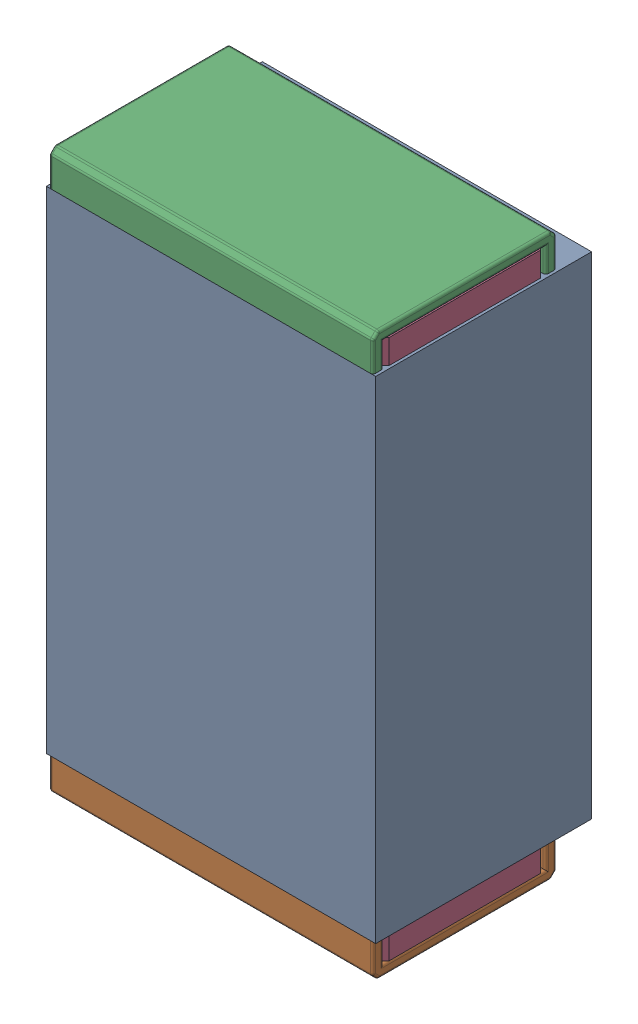
SolidWorks assembly R25, configuration Default. Lengths in mm.
Overall size (0.61 1.04 0.4).
3 component instances, 2 part files, 0 mates.
Components (placement in the parent):
- 1088881848-1: 1088881848 [Default] at (1.425 2.8 -2.044) size (0.61 0.91 0.4)
  - Extruded-1-1: Extruded-1 [Default] at origin size (0.61 0.91 0.4)
- R0402-1: R0402 [Default] at (1.425 2.8 -1.644) x (0 -1 0) z (1 0 0) size (1.04 0.34 0.6)
